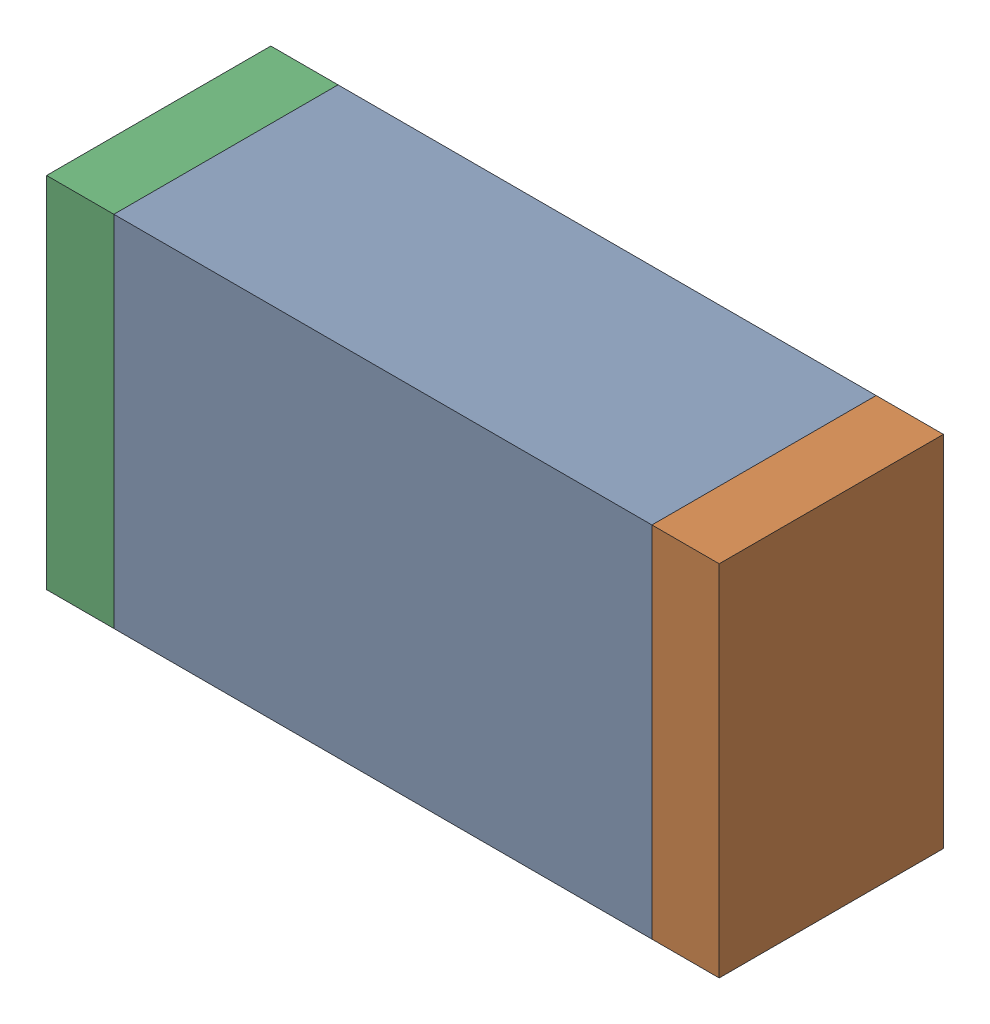
SolidWorks assembly R60, configuration Default. Lengths in mm.
Overall size (1.5 0.8 0.5).
6 component instances, 2 part files, 0 mates.
Components (placement in the parent):
- 836752368-1: 836752368 [Default] at (124.05 70.7 0) size (1.2 0.8 0.5)
  - Extruded-1: Extruded [Default] at origin size (1.2 0.8 0.5)
- 836752496-1: 836752496 [Default] at (124.725 70.7 0) size (0.15 0.8 0.5)
  - Extruded_2-1: Extruded_2 [Default] at origin size (0.15 0.8 0.5)
- 836752496-2: 836752496 [Default] at (123.375 70.7 0) size (0.15 0.8 0.5)
  - Extruded_2-1: Extruded_2 [Default] at origin size (0.15 0.8 0.5)
